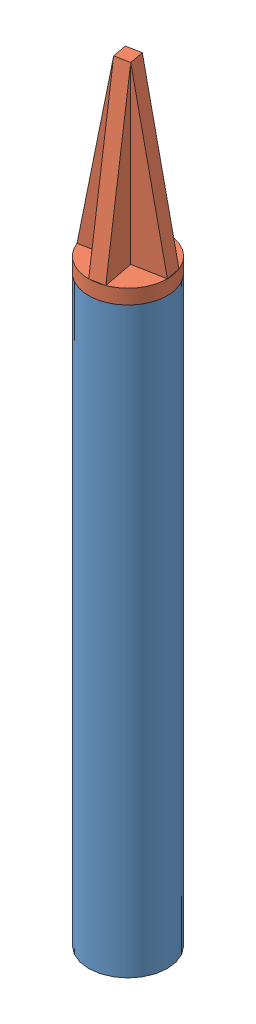
SolidWorks assembly Assembly, configuration Default. Lengths in mm.
Overall size (31.56 278.32 31.56).
2 component instances, 2 part files, 2 mates.
Components (placement in the parent):
- Postolje-1: Postolje [Default] at origin size (27 200 27)
- Spica-1: Spica [Default] at (0 185 0) x (-0.186328 0 -0.982488) z (0.982488 0 -0.186328) size (27 93.32 27)
Mates (geometry in assembly coordinates):
- Concentric1: concentric: cylinder of Postolje-1 through (0 200 0) axis (0 -1 0) radius 10.5; cylinder of Spica-1 through (0 200 0) axis (0 -1 0) radius 10.5
- Coincident1: coincident: plane of Postolje-1 through (0 200 0) normal (0 1 0); plane of Spica-1 through (0 200 0) normal (0 -1 0)
